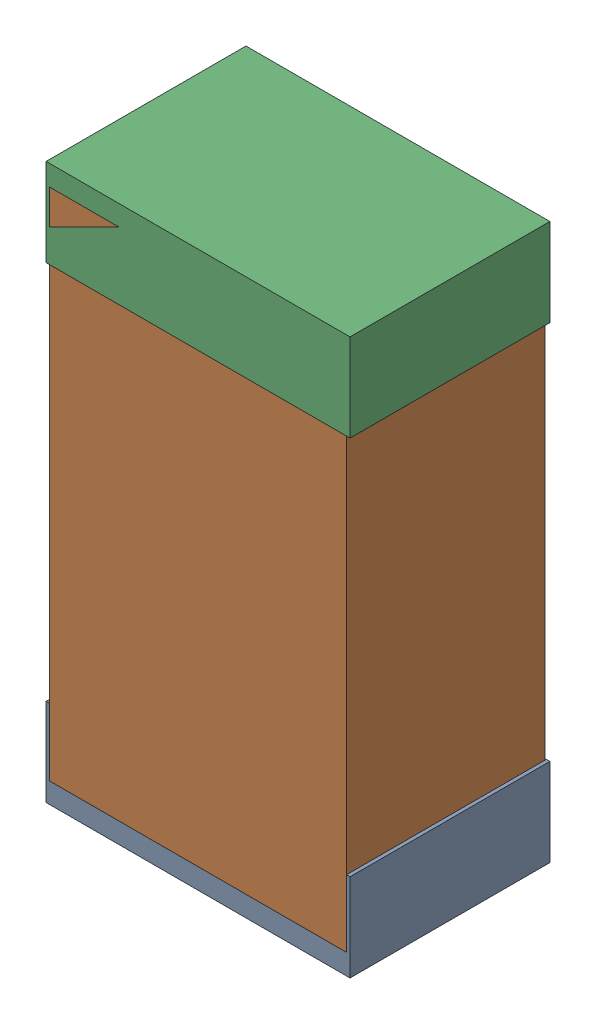
SolidWorks assembly R10Kanaloa_v2.0.0_Motor, configuration Default. Lengths in mm.
Overall size (1.3 2.38 0.85).
6 component instances, 2 part files, 0 mates.
Components (placement in the parent):
- 330415056-1: 330415056 [Default] at (43.688 70.12 -1.9574) size (1.3 0.38 0.85)
  - Extruded_2-1: Extruded_2 [Default] at origin size (1.3 0.38 0.85)
- 334787376-1: 334787376 [Default] at (43.688 71.12 -1.9524) size (1.27 2.2 0.85)
  - Extruded_16-1: Extruded_16 [Default] at origin size (1.27 2.2 0.85)
- 330415056-2: 330415056 [Default] at (43.688 72.12 -1.9574) size (1.3 0.38 0.85)
  - Extruded_2-1: Extruded_2 [Default] at origin size (1.3 0.38 0.85)
